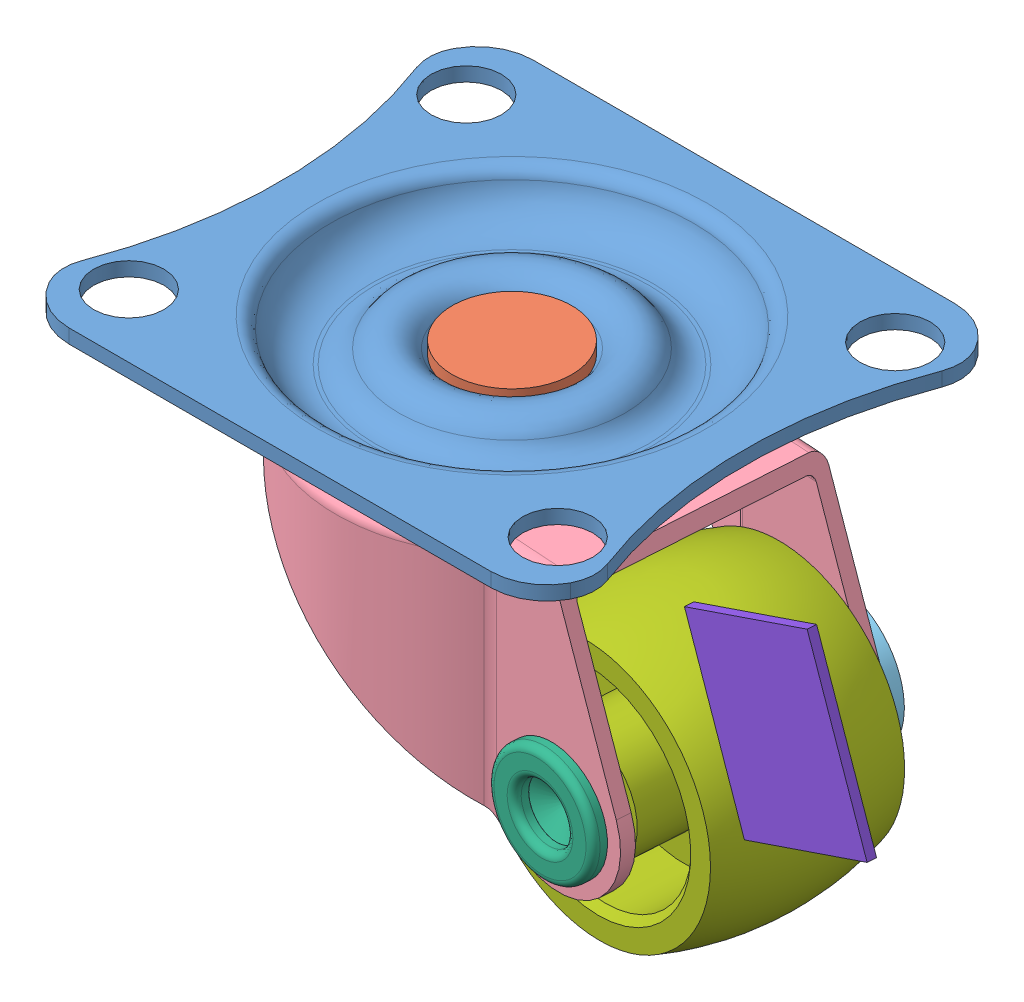
SolidWorks assembly Caster Wheel d=20mm, configuration Défaut. Lengths in mm.
Overall size (104.02 31.97 42.2).
10 component instances, 8 part files, 8 mates.
Components (placement in the parent):
- A - Base-1: A - Base [Défaut] at (1.134 3.654 0) size (104.02 8 42.2)
  - Base-1: Base [Défaut] at (-1.008 2.021 37.7647) size (37.76 4 33)
  - Rivet A-1: Rivet A [Défaut] at (-1.008 -0.979 37.7647) size (8.5 5.5 8.5)
  - Rivet B-1: Rivet B [Défaut] at (-1.008 -3.979 37.7647) size (10.5 5 10.5)
- B - Chape-1: B - Chape [Défaut] at (3.7589 -7.2218 6.9338) x (0.997956 0 0.063898) z (-0.063898 0 0.997956) size (31 19 25)
  - Chape-1: Chape [Défaut] at (11.8446 -6.1032 31) size (31 19 25)
  - Rivet2 A-1: Rivet2 A [Défaut] at (11.8446 -6.1032 22) size (10 10 19.48)
  - Rivet2 B-1: Rivet2 B [Défaut] at (11.8446 -6.1032 40) x (0 0 -1) z (0.975007 0.222176 0) size (14 8 8)
- C - Galet-1: C - Galet [Défaut] at (13.5984 -13.325 38.6273) x (0.994184 -0.086867 0.063656) z (-0.063898 0 0.997956) size (20 20 14)
- Part2^Caster Wheel d=20mm-1: Part2^Caster Wheel d=20mm [Default] at (18.2591 -11.5393 38.9257) x (0.063898 0 -0.997956) z (0.932141 0.357143 0.059684) size (8.63 13.08 20) (virtual)
Mates (geometry in assembly coordinates):
- Coaxiale1: concentric aligned: cylinder of A - Base-1/Base-1 through (0.126 11.0488 37.7647) axis (0 1 0) radius 1.5; cylinder of B - Chape-1/Chape-1 through (0.126 -18.325 37.7647) axis (0 1 0) radius 1.5
- Distance1: distance = 5 mm aligned: plane of A - Base-1/Base-1 through (-14.874 5.675 37.7647) normal (0 1 0); plane of B - Chape-1/Chape-1 through (-12.9235 0.675 45.9476) normal (0 1 0)
- Coaxiale2: concentric aligned: cylinder of B - Chape-1/Chape-1 through (14.1735 -13.325 29.6457) axis (-0.063898 0 0.997956) radius 3; cylinder of C - Galet-1 through (13.2972 -13.325 43.3324) axis (-0.063898 0 0.997956) radius 3
- Distance2: distance = 1 mm anti-aligned: plane of C - Galet-1 through (14.3058 -10.3363 31.6583) normal (0.063898 0 -0.997956); plane of B - Chape-1/Chape-1 through (-11.8373 0.675 28.9823) normal (-0.063898 0 0.997956)
- InPlace1: in place: plane of B - Chape-1/Chape-1 through (18.8342 -11.5393 29.9441) normal (0.932141 0.357143 0.059684); plane of ? through (14.1892 5.4365 0.9085) normal (0.932141 0.357143 0.059684); moOrthogonalPlaneRef_w of B - Chape-1/Chape-1 through (18.8342 -11.5393 29.9441) normal (0.932141 0.357143 0.059684); plane of ? through (14.1892 5.4365 0.9085) normal (-0.357781 0.933806 0); plane of B - Chape-1/Chape-1 through (18.8342 -11.5393 29.9441) normal (0.932141 0.357143 0.059684); plane of ? through (14.1892 5.4365 0.9085) normal (0.055733 0.021354 -0.998217); plane of B - Chape-1/Chape-1 through (18.8342 -11.5393 29.9441) normal (0.932141 0.357143 0.059684); unknown of Part2^Caster Wheel d=20mm-1
- Coincident1: coincident aligned: plane of B - Chape-1/Chape-1; plane of Part2^Caster Wheel d=20mm-1
- Coincident2: coincident aligned: moOrthogonalPlaneRef_w of B - Chape-1/Chape-1 through (18.2591 -11.5393 38.9257) normal (-0.356413 0.93405 -0.022821); plane of Part2^Caster Wheel d=20mm-1 through (18.2591 -11.5393 38.9257) normal (-0.356413 0.93405 -0.022821)
- Coincident3: coincident anti-aligned: moOrthogonalPlaneRef_w of B - Chape-1/Chape-1 through (18.2591 -11.5393 38.9257) normal (-0.063898 0 0.997956); plane of Part2^Caster Wheel d=20mm-1 through (18.2591 -11.5393 38.9257) normal (0.063898 0 -0.997956)
